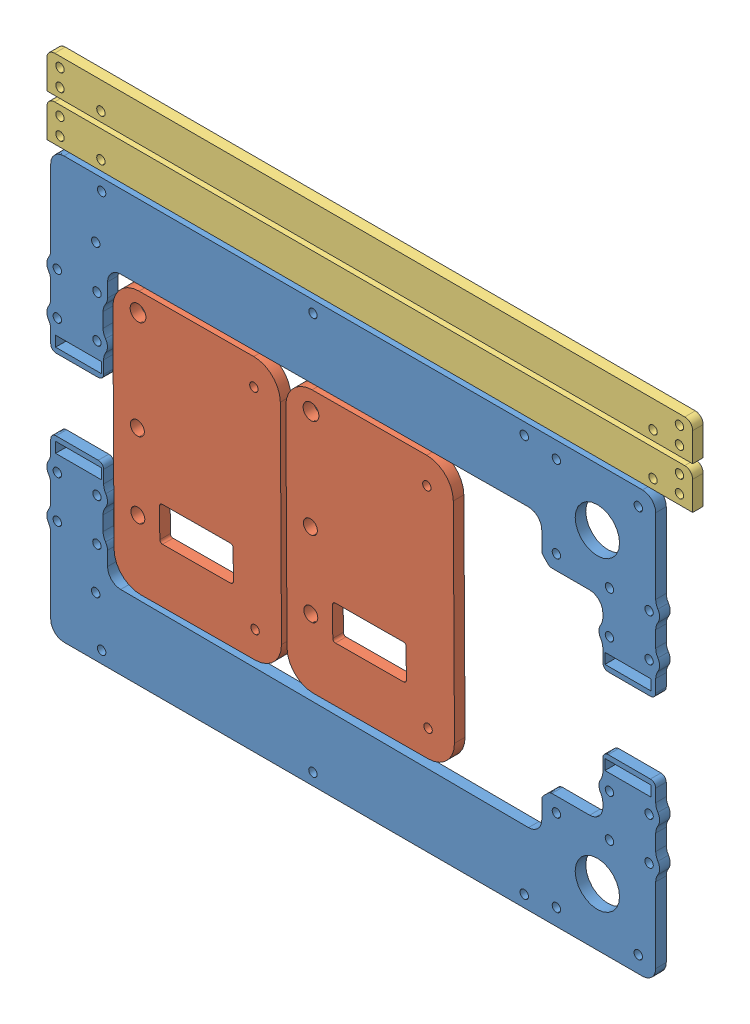
SolidWorks assembly X FRAME  incomplete 0.6mm increment, configuration Default. Lengths in mm.
Overall size (250 200 4).
7 component instances, 4 part files, 27 mates.
Components (placement in the parent):
- X Bridge 4-1: X Bridge 4 [Valor predeterminado] at (-97.88 -11.4267 0) size (232 66.16 4)
- X Bridge 4-2: X Bridge 4 [Valor predeterminado] at (-97.88 -2.0391 4) x (1 0 0) z (0 0 -1) size (232 66.16 4)
- Small foot2-4: Small foot2 [Default] at (-232.4394 -324.5343 0) x (-0.999984 -0.00574 0) z (0 0 1) size (63.38 99.24 4)
- Small foot2-5: Small foot2 [Default] at (-166.9563 -324.1584 0) x (-0.999984 -0.00574 0) z (0 0 1) size (63.38 99.24 4)
- CONECTION-1: CONECTION [Default] at (-270.2307 -22.6802 0) x (0 1 0) z (0 0 1) (suppressed, hidden)
- Handle-1: Handle [Default] at (-32.5 15.508 0) size (244.5 13.87 4)
- Handle-2: Handle [Default] at (-32.5 -0.4578 0) size (244.5 13.87 4)
Mates (geometry in assembly coordinates):
- Parallel3: parallel anti-aligned: plane of X Bridge 4-2 through (-70.88 -100.5949 0) normal (0 -1 0); plane of Small foot2-5
- Coincident15: coincident anti-aligned: plane of X Bridge 4-1 through (-97.88 -11.4267 0) normal (0 0 -1); plane of assembly through (0 0 0) normal (0 0 1)
- Coincident17: coincident aligned: plane of X Bridge 4-1 through (-97.88 -11.4267 4) normal (0 0 1); plane of Small foot2-4 through (-232.4394 -324.5343 4) normal (0 0 1)
- Parallel4: parallel anti-aligned: plane of X Bridge 4-1 through (-97.88 72.9814 4) normal (0 1 0); plane of Handle-2 through (30.0711 75.0814 4) normal (0 -1 0)
- Coincident20: coincident anti-aligned: line of ? through (38.0748 99.4051 0) axis (-1 0 0)
- Parallel5: parallel aligned: line of assembly; line of X Bridge 4-2 through (-212.9289 -81.4472 0) axis (0 1 0)
- Coincident27: coincident aligned: plane of X Bridge 4-1 through (-97.88 -11.4267 0) normal (0 0 -1); plane of X Bridge 4-2 through (-97.88 -2.0391 0) normal (0 0 -1)
- Distance19: distance = 1 mm: cylinder of X Bridge 4-1 through (-210.4289 18.5906 4) axis (0 0 -1) radius 4; line of assembly
- Coincident33: coincident aligned: plane of X Bridge 4-1 through (-97.88 -11.4267 4) normal (0 0 1); plane of Small foot2-5 through (-166.9563 -324.1584 4) normal (0 0 1)
- Distance5: distance = 2 mm anti-aligned: plane of Small foot2-4 through (-106.6664 -53.0476 4) normal (0.999984 0.00574 0); plane of Small foot2-5 through (-41.7529 46.5663 4) normal (-0.00574 0.999984 0)
- Coincident38: coincident aligned: plane of X Bridge 4-1 through (-97.88 -11.4267 0) normal (0 0 -1); plane of CONECTION-1 through (-270.2307 -22.6802 0) normal (0 0 -1)
- Parallel6: parallel anti-aligned: plane of Small foot2-4 through (-125.5152 -56.0468 4) normal (0.999984 0.00574 0); plane of Small foot2-5 through (-123.4152 -56.0347 4) normal (-0.999984 -0.00574 0)
- Distance9: distance = 2.1 mm anti-aligned: plane of Small foot2-5 through (-123.4152 -56.0347 4) normal (-0.999984 -0.00574 0); plane of Small foot2-4 through (-125.5152 -56.0468 4) normal (0.999984 0.00574 0)
- Coincident45: coincident aligned: plane of X Bridge 4-1 through (-97.88 -11.4267 4) normal (0 0 1); plane of Handle-1 through (27.0711 101.9131 4) normal (0 0 1)
- Distance17: distance = 1 mm: plane of Handle-1 through (-214.4289 101.9131 4) normal (-1 0 0); line of assembly
- Distance10: distance = 2.1 mm anti-aligned: plane of Handle-2 through (27.0711 88.9473 4) normal (0 1 0); plane of Handle-1 through (30.0711 91.0473 4) normal (0 -1 0)
- Coincident49: coincident aligned: plane of Handle-1 through (27.0711 101.9131 4) normal (0 0 1); plane of Handle-2 through (27.0711 85.9473 4) normal (0 0 1)
- Coincident50: coincident aligned: plane of Handle-1 through (-214.4289 101.9131 4) normal (-1 0 0); plane of Handle-2 through (-214.4289 85.9473 4) normal (-1 0 0)
- Coincident51: coincident aligned: plane of Small foot2-4 through (-125.5152 -56.0468 4) normal (0.00574 -0.999984 0); plane of Small foot2-5 through (-60.032 -55.6709 4) normal (0.00574 -0.999984 0)
- Distance11: distance = 2.1 mm anti-aligned: plane of X Bridge 4-1 through (-97.88 72.9814 4) normal (0 1 0); plane of Handle-2 through (30.0711 75.0814 4) normal (0 -1 0)
- Distance13: distance = 2.1 mm anti-aligned: plane of Small foot2-4 through (-126.0848 43.1912 4) normal (-0.00574 0.999984 0); plane of X Bridge 4-1 through (-98.2065 45.4513 4) normal (0.00574 -0.999984 0)
- Distance14: distance = 2.1 mm anti-aligned: cylinder of X Bridge 4-1 through (13.5748 18.5906 4) axis (0 0 -1) radius 4; plane of CONECTION-1 through (19.6748 -85.9992 4) normal (-1 0 0)
- Distance20: distance = 1 mm: cylinder of X Bridge 4-2 through (-210.4289 -48.0564 0) axis (0 0 1) radius 4; line of assembly
- Distance15: distance = 2.1 mm anti-aligned: cylinder of Small foot2-4 through (-178.9559 -46.3534 4) axis (0 0 -1) radius 10; plane of X Bridge 4-2 through (-98.2065 -58.9171 0) normal (0.00574 0.999984 0)
- Distance16: distance = 2.1 mm anti-aligned: plane of CONECTION-1 through (19.6748 72.9814 4) normal (0 1 0); plane of Handle-2 through (30.0711 75.0814 4) normal (0 -1 0)
- Distance21: distance = 1 mm: plane of Handle-1 through (27.0711 104.9131 4) normal (0 1 0); line of assembly
- Distance22: distance = 2.1 mm anti-aligned: plane of Small foot2-4 through (-188.8983 -56.4106 4) normal (-0.999984 -0.00574 0); cylinder of X Bridge 4-1 through (-195.4289 18.5906 4) axis (0 0 -1) radius 4
